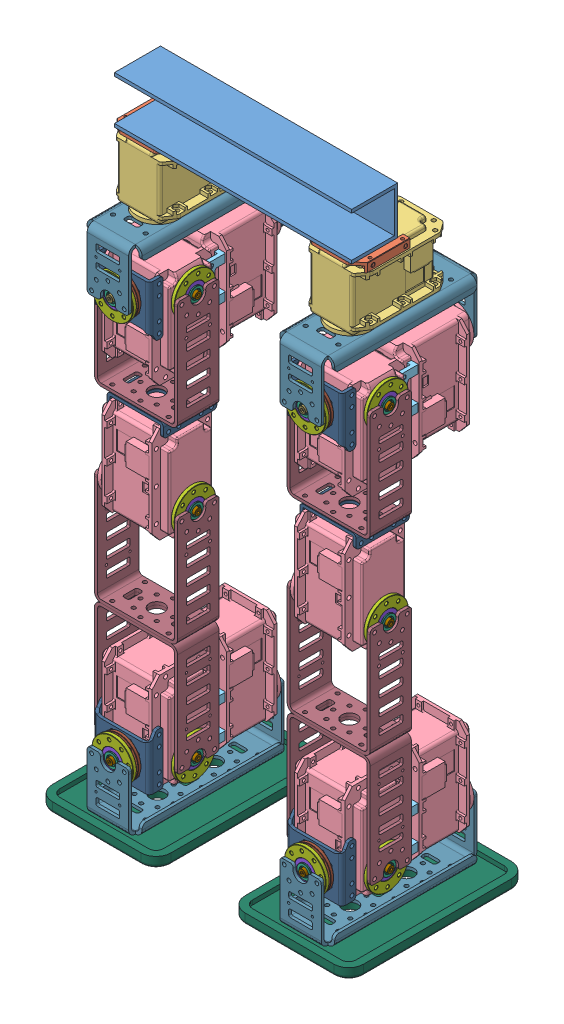
SolidWorks assembly leg, configuration Default. Lengths in mm.
Overall size (275.63 438.68 145.63).
96 component instances, 15 part files, 40 mates.
Components (placement in the parent):
- leg_l0-1: leg_l0 [Default] at origin size (170.2 83 62.1)
  - leg_body0-1: leg_body0 [Default] x (1 0 0) z (0 1 0) size (160 31 32)
  - FR05-B101_2017-1: FR05-B101_2017 [Default] at (-65 -39 -14) x (1 0 0) z (0 -1 0) size (39 35 6)
  - FR05-B101_2017-2: FR05-B101_2017 [Default] at (65 -39 -14) x (1 0 0) z (0 -1 0) size (39 35 6)
  - MX-64T_step-1: MX-64T_step [Default] at (-65 -39 -14) x (1 0 0) z (0 -1 0) size (40.2 62.1 50)
  - MX-64T_step-2: MX-64T_step [Default] at (65 -39 -14) x (1 0 0) z (0 -1 0) size (40.2 62.1 50)
- leg_l2-1: leg_l2 [Default] at (-65 -99.5 -13.5) x (0 0 1) z (-1 0 0) size (106.88 70.06 58.88)
  - MX-106T_step-1: MX-106T_step [Default] at origin size (40.2 65.92 55.3)
  - MX-106T_step-2: MX-106T_step [Default] at (-44 0 0) x (0 0 1) z (-1 0 0) size (40.2 65.92 55.3)
  - FR08-X101_2017-1: FR08-X101_2017 [Default] at (-27 -7 -17) x (0 -1 0) z (0 0 1) size (28 12.3 4.8)
  - FR08-X101_2017-2: FR08-X101_2017 [Default] at (-27 -7 17) x (0 1 0) z (0 0 -1) size (28 12.3 4.8)
  - RX64-CAP_2017-1: RX64-CAP_2017 [Default] at (0 0 -25.78) x (0.56381 0.825904 0) z (0 0 -1) size (9.5 9.5 2.2)
  - HN05-I101_2017-1: HN05-I101_2017 [Default] at (0 0 -26.02) x (0.824833 -0.565376 0) z (0.565376 0.824833 0) size (28 3.77 28)
  - MF128ZZ_2017-1: MF128ZZ_2017 [Default] at (0 0 -22.3) x (-0.923728 -0.383049 0) z (0.383049 -0.923728 0) size (14 3.48 14)
  - WB_M2.5X8_2017-1: WB_M2.5X8_2017 [Default] at (0 0 -28.08) x (0 0 1) z (0.825904 -0.56381 0) size (5.5 4.5 4.5)
  - FR05-S101_2017-1: FR05-S101_2017 [Default] at (24 0 0) x (0 1 0) z (0 0 1) size (36 9.31 38.02)
  - FR05-F101_2017-1: FR05-F101_2017 [Default] at (24 0 0) x (0 -0.707107 0.707107) z (1 0 0) size (27 27 5)
  - MF128ZZ_2017-2: MF128ZZ_2017 [Default] at (26.3 0 0) x (0 -1 0) z (0 0 1) size (14 3.48 14)
  - WB_M2.5X8_step-1: WB_M2.5X8_step [Default] at (32.08 0 0) x (-1 0 0) z (0 0.546944 0.837169) size (10.5 4.5 4.5)
  - HN05-I101_2017-2: HN05-I101_2017 [Default] at (30.02 0 0) x (0 -1 0) z (0 0 1) size (28 3.77 28)
  - RX64-CAP_2017-2: RX64-CAP_2017 [Default] at (29.78 0 0) x (0 0.837169 -0.546944) z (1 0 0) size (9.5 9.5 2.2)
- leg_l3-2: leg_l3 [Default] at (-87.8152 -185.4067 38.733) x (1 0 0) z (0 1 0) size (58.88 41.6 149.21)
  - HW-64106HXL_2017-1: HW-64106HXL_2017 [Default] at (-3.1848 38.233 13.9067) size (56 28 75)
  - FR05-S101_2017-1: FR05-S101_2017 [Default] at (22.8152 52.233 13.9067) x (0 -1 0) z (1 0 0) size (36 9.31 38.02)
  - MX-106T_step-1: MX-106T_step [Default] at (22.8152 52.233 -40.5933) x (0 1 0) z (-1 0 0) size (40.2 65.92 55.3)
  - HN05-I101_2017-1: HN05-I101_2017 [Default] at (48.8352 52.233 -40.5933) x (0 -0.637924 -0.7701) z (0 -0.7701 0.637924) size (28 3.77 28)
  - RX64-CAP_2017-1: RX64-CAP_2017 [Default] at (48.5952 52.233 -40.5933) x (0 0.837169 -0.546944) z (1 0 0) size (9.5 9.5 2.2)
  - MF128ZZ_2017-1: MF128ZZ_2017 [Default] at (45.1152 52.233 -40.5933) x (0 -0.162836 -0.986653) z (0 -0.986653 0.162836) size (14 3.48 14)
  - WB_M2.5X8_2017-1: WB_M2.5X8_2017 [Default] at (50.8952 52.233 -40.5933) x (-1 0 0) z (0 0.546944 0.837169) size (5.5 4.5 4.5)
- leg_l4-1: leg_l4 [Default] at (-107.1663 -366.6685 32.4894) x (1 0 0) z (0 1 0) size (56 28 150)
  - HW-64106HXL_2017-1: HW-64106HXL_2017 [Default] at (16.1663 31.9894 68.6685) size (56 28 75)
  - HW-64106HXL_2017-2: HW-64106HXL_2017 [Default] at (68.1663 31.9894 68.6685) x (-1 0 0) z (0 0 -1) size (56 28 75)
- leg_l5-1: leg_l5 [Default] at (-20.4188 -316.682 -47.3723) x (0.699193 -0.033567 0.714144) z (-0.673395 -0.366444 0.642073) size (104.02 99.97 119.36)
  - MX-106T_step-1: MX-106T_step [Default] at (-5.1915 -29.4269 71.3073) x (-0.714144 -0.278818 -0.642073) z (-0.699193 0.240141 0.673395) size (40.2 65.92 55.3)
  - MX-106T_step-2: MX-106T_step [Default] at (-36.6138 -41.6949 43.056) x (0.699193 -0.240141 -0.673395) z (-0.714144 -0.278818 -0.642073) size (40.2 65.92 55.3)
  - FR08-X101_2017-1: FR08-X101_2017 [Default] at (-36.5946 -26.3638 62.8539) x (-0.033567 0.929835 -0.366444) z (0.699193 -0.240141 -0.673395) size (28 12.3 4.8)
  - FR08-X101_2017-2: FR08-X101_2017 [Default] at (-12.8221 -34.5286 39.9585) x (0.033567 -0.929835 0.366444) z (-0.699193 0.240141 0.673395) size (28 12.3 4.8)
  - HN05-I101_2017-1: HN05-I101_2017 [Default] at (13.0015 -35.6754 53.7855) x (0.048348 -0.923861 0.379661) z (0.713296 0.298014 0.634347) size (28 3.77 28)
  - RX64-CAP_2017-1: RX64-CAP_2017 [Default] at (12.8337 -35.6178 53.9472) x (-0.430608 0.610431 -0.664793) z (0.699193 -0.240141 -0.673395) size (9.5 9.5 2.2)
  - HN05-I101_2017-2: HN05-I101_2017 [Default] at (16.2471 -21.0568 90.5823) x (0.601193 -0.714144 -0.35856) z (-0.35856 -0.642073 0.677626) size (28 3.77 28)
  - RX64-CAP_2017-2: RX64-CAP_2017 [Default] at (16.0757 -21.1237 90.4282) x (-0.307188 0.949038 -0.070448) z (0.714144 0.278818 0.642073) size (9.5 9.5 2.2)
  - MF128ZZ_2017-1: MF128ZZ_2017 [Default] at (10.4005 -34.7821 56.2906) x (0.048348 -0.923861 0.379661) z (0.713296 0.298014 0.634347) size (14 3.48 14)
  - WB_M2.5X8_2017-1: WB_M2.5X8_2017 [Default] at (14.4419 -36.1701 52.3983) x (-0.699193 0.240141 0.673395) z (0.570706 0.754788 0.323403) size (5.5 4.5 4.5)
  - MF128ZZ_2017-2: MF128ZZ_2017 [Default] at (13.5905 -22.094 88.1938) x (0.601193 -0.714144 -0.35856) z (-0.35856 -0.642073 0.677626) size (14 3.48 14)
  - WB_M2.5X8_2017-2: WB_M2.5X8_2017 [Default] at (17.7183 -20.4824 91.905) x (-0.714144 -0.278818 -0.642073) z (-0.628994 -0.146927 0.763399) size (5.5 4.5 4.5)
  - FR05-S101_2017-1: FR05-S101_2017 [Default] at (11.948 -22.7353 86.717) x (0.033567 -0.929835 0.366444) z (0.699193 -0.240141 -0.673395) size (36 9.31 38.02)
  - FR05-F101_2017-1: FR05-F101_2017 [Default] at (11.948 -22.7353 86.717) x (0.699193 -0.240141 -0.673395) z (0.714144 0.278818 0.642073) size (27 27 5)
- leg_l6-1: leg_l6 [Default] at (-15.5913 -468.4394 11.5308) x (0 0 -1) z (0 1 0) size (120 80 44)
  - HW-64106HXW_2017-1: HW-64106HXW_2017 [Default] at (-3.9692 33.4087 61.4394) size (105 37.08 40)
  - foot_2017-1: foot_2017 [Default] at (44.5308 49.4087 57.4394) x (-1 0 0) z (0 1 0) size (120 7 80)
- HW-64106HXW_2017-3: HW-64106HXW_2017 [Default] at (81 -62.5 -81.5) x (0 0 1) z (0 -1 0) size (105 37.08 40)
- leg_l2-2: leg_l2 [Default] at (65 -99.5 -13.5) x (0 0 1) z (-1 0 0) size (106.88 70.06 58.88)
  - MX-106T_step-1: MX-106T_step [Default] at origin size (40.2 65.92 55.3)
  - MX-106T_step-2: MX-106T_step [Default] at (-44 0 0) x (0 0 1) z (-1 0 0) size (40.2 65.92 55.3)
  - FR08-X101_2017-1: FR08-X101_2017 [Default] at (-27 -7 -17) x (0 -1 0) z (0 0 1) size (28 12.3 4.8)
  - FR08-X101_2017-2: FR08-X101_2017 [Default] at (-27 -7 17) x (0 1 0) z (0 0 -1) size (28 12.3 4.8)
  - RX64-CAP_2017-1: RX64-CAP_2017 [Default] at (0 0 -25.78) x (0.56381 0.825904 0) z (0 0 -1) size (9.5 9.5 2.2)
  - HN05-I101_2017-1: HN05-I101_2017 [Default] at (0 0 -26.02) x (0.824833 -0.565376 0) z (0.565376 0.824833 0) size (28 3.77 28)
  - MF128ZZ_2017-1: MF128ZZ_2017 [Default] at (0 0 -22.3) x (-0.923728 -0.383049 0) z (0.383049 -0.923728 0) size (14 3.48 14)
  - WB_M2.5X8_2017-1: WB_M2.5X8_2017 [Default] at (0 0 -28.08) x (0 0 1) z (0.825904 -0.56381 0) size (5.5 4.5 4.5)
  - FR05-S101_2017-1: FR05-S101_2017 [Default] at (24 0 0) x (0 1 0) z (0 0 1) size (36 9.31 38.02)
  - FR05-F101_2017-1: FR05-F101_2017 [Default] at (24 0 0) x (0 -0.707107 0.707107) z (1 0 0) size (27 27 5)
  - MF128ZZ_2017-2: MF128ZZ_2017 [Default] at (26.3 0 0) x (0 -1 0) z (0 0 1) size (14 3.48 14)
  - WB_M2.5X8_step-1: WB_M2.5X8_step [Default] at (32.08 0 0) x (-1 0 0) z (0 0.546944 0.837169) size (10.5 4.5 4.5)
  - HN05-I101_2017-2: HN05-I101_2017 [Default] at (30.02 0 0) x (0 -1 0) z (0 0 1) size (28 3.77 28)
  - RX64-CAP_2017-2: RX64-CAP_2017 [Default] at (29.78 0 0) x (0 0.837169 -0.546944) z (1 0 0) size (9.5 9.5 2.2)
- leg_l3-3: leg_l3 [Default] at (42.1848 -185.4067 38.733) x (1 0 0) z (0 1 0) size (58.88 41.6 149.21)
  - HW-64106HXL_2017-1: HW-64106HXL_2017 [Default] at (-3.1848 38.233 13.9067) size (56 28 75)
  - FR05-S101_2017-1: FR05-S101_2017 [Default] at (22.8152 52.233 13.9067) x (0 -1 0) z (1 0 0) size (36 9.31 38.02)
  - MX-106T_step-1: MX-106T_step [Default] at (22.8152 52.233 -40.5933) x (0 1 0) z (-1 0 0) size (40.2 65.92 55.3)
  - HN05-I101_2017-1: HN05-I101_2017 [Default] at (48.8352 52.233 -40.5933) x (0 -0.637924 -0.7701) z (0 -0.7701 0.637924) size (28 3.77 28)
  - RX64-CAP_2017-1: RX64-CAP_2017 [Default] at (48.5952 52.233 -40.5933) x (0 0.837169 -0.546944) z (1 0 0) size (9.5 9.5 2.2)
  - MF128ZZ_2017-1: MF128ZZ_2017 [Default] at (45.1152 52.233 -40.5933) x (0 -0.162836 -0.986653) z (0 -0.986653 0.162836) size (14 3.48 14)
  - WB_M2.5X8_2017-1: WB_M2.5X8_2017 [Default] at (50.8952 52.233 -40.5933) x (-1 0 0) z (0 0.546944 0.837169) size (5.5 4.5 4.5)
- leg_l4-2: leg_l4 [Default] at (22.8337 -366.6685 32.4894) x (1 0 0) z (0 1 0) size (56 28 150)
  - HW-64106HXL_2017-1: HW-64106HXL_2017 [Default] at (16.1663 31.9894 68.6685) size (56 28 75)
  - HW-64106HXL_2017-2: HW-64106HXL_2017 [Default] at (68.1663 31.9894 68.6685) x (-1 0 0) z (0 0 -1) size (56 28 75)
- leg_l5-2: leg_l5 [Default] at (109.5812 -316.682 -47.3723) x (0.699193 -0.033567 0.714144) z (-0.673395 -0.366444 0.642073) size (104.02 99.97 119.36)
  - MX-106T_step-1: MX-106T_step [Default] at (-5.1915 -29.4269 71.3073) x (-0.714144 -0.278818 -0.642073) z (-0.699193 0.240141 0.673395) size (40.2 65.92 55.3)
  - MX-106T_step-2: MX-106T_step [Default] at (-36.6138 -41.6949 43.056) x (0.699193 -0.240141 -0.673395) z (-0.714144 -0.278818 -0.642073) size (40.2 65.92 55.3)
  - FR08-X101_2017-1: FR08-X101_2017 [Default] at (-36.5946 -26.3638 62.8539) x (-0.033567 0.929835 -0.366444) z (0.699193 -0.240141 -0.673395) size (28 12.3 4.8)
  - FR08-X101_2017-2: FR08-X101_2017 [Default] at (-12.8221 -34.5286 39.9585) x (0.033567 -0.929835 0.366444) z (-0.699193 0.240141 0.673395) size (28 12.3 4.8)
  - HN05-I101_2017-1: HN05-I101_2017 [Default] at (13.0015 -35.6754 53.7855) x (0.048348 -0.923861 0.379661) z (0.713296 0.298014 0.634347) size (28 3.77 28)
  - RX64-CAP_2017-1: RX64-CAP_2017 [Default] at (12.8337 -35.6178 53.9472) x (-0.430608 0.610431 -0.664793) z (0.699193 -0.240141 -0.673395) size (9.5 9.5 2.2)
  - HN05-I101_2017-2: HN05-I101_2017 [Default] at (16.2471 -21.0568 90.5823) x (0.601193 -0.714144 -0.35856) z (-0.35856 -0.642073 0.677626) size (28 3.77 28)
  - RX64-CAP_2017-2: RX64-CAP_2017 [Default] at (16.0757 -21.1237 90.4282) x (-0.307188 0.949038 -0.070448) z (0.714144 0.278818 0.642073) size (9.5 9.5 2.2)
  - MF128ZZ_2017-1: MF128ZZ_2017 [Default] at (10.4005 -34.7821 56.2906) x (0.048348 -0.923861 0.379661) z (0.713296 0.298014 0.634347) size (14 3.48 14)
  - WB_M2.5X8_2017-1: WB_M2.5X8_2017 [Default] at (14.4419 -36.1701 52.3983) x (-0.699193 0.240141 0.673395) z (0.570706 0.754788 0.323403) size (5.5 4.5 4.5)
  - MF128ZZ_2017-2: MF128ZZ_2017 [Default] at (13.5905 -22.094 88.1938) x (0.601193 -0.714144 -0.35856) z (-0.35856 -0.642073 0.677626) size (14 3.48 14)
  - WB_M2.5X8_2017-2: WB_M2.5X8_2017 [Default] at (17.7183 -20.4824 91.905) x (-0.714144 -0.278818 -0.642073) z (-0.628994 -0.146927 0.763399) size (5.5 4.5 4.5)
  - FR05-S101_2017-1: FR05-S101_2017 [Default] at (11.948 -22.7353 86.717) x (0.033567 -0.929835 0.366444) z (0.699193 -0.240141 -0.673395) size (36 9.31 38.02)
  - FR05-F101_2017-1: FR05-F101_2017 [Default] at (11.948 -22.7353 86.717) x (0.699193 -0.240141 -0.673395) z (0.714144 0.278818 0.642073) size (27 27 5)
- leg_l6-2: leg_l6 [Default] at (114.4087 -468.4394 11.5308) x (0 0 -1) z (0 1 0) size (120 80 44)
  - HW-64106HXW_2017-1: HW-64106HXW_2017 [Default] at (-3.9692 33.4087 61.4394) size (105 37.08 40)
  - foot_2017-1: foot_2017 [Default] at (44.5308 49.4087 57.4394) x (-1 0 0) z (0 1 0) size (120 7 80)
- HW-64106HXW_2017-5: HW-64106HXW_2017 [Default] at (-49 -62.5 -81.5) x (0 0 1) z (0 -1 0) size (105 37.08 40)
Mates (geometry in assembly coordinates):
- Concentric3: concentric anti-aligned: cylinder of leg_l2-1/HN05-I101_2017-1 through (-38.98 -99.5 -13.5) axis (-1 0 0) radius 14; cylinder of leg_l3-2/HW-64106HXL_2017-1 through (-37 -99.5 -13.5) axis (1 0 0) radius 5.1
- Concentric4: concentric anti-aligned: cylinder of leg_l3-2/HN05-I101_2017-1 through (-38.98 -226 -13.5) axis (-1 0 0) radius 14; cylinder of leg_l4-1/HW-64106HXL_2017-1 through (-37 -226 -13.5) axis (1 0 0) radius 5.1
- Concentric5: concentric anti-aligned: cylinder of leg_l4-1/HW-64106HXL_2017-2 through (-93 -370 -13.5) axis (-1 0 0) radius 5.1; cylinder of leg_l5-1/MX-106T_step-1 through (-96.19 -370 -13.5) axis (1 0 0) radius 5
- Coincident5: coincident anti-aligned: plane of leg_l4-1/HW-64106HXL_2017-2 through (-91 -370 -13.5) normal (1 0 0); plane of leg_l5-1/MX-106T_step-1 through (-91 -370 -13.5) normal (-1 0 0)
- Coincident6: coincident anti-aligned: plane of leg_l2-1/MX-106T_step-1 through (-91 -99.5 -13.5) normal (-1 0 0); plane of leg_l3-2/HW-64106HXL_2017-1 through (-91 -99.5 -13.5) normal (1 0 0)
- Coincident7: coincident anti-aligned: plane of leg_l2-1/MX-106T_step-1 through (-91 -99.5 -13.5) normal (-1 0 0); plane of leg_l3-2/HW-64106HXL_2017-1 through (-91 -99.5 -13.5) normal (1 0 0)
- Coincident8: coincident anti-aligned: plane of leg_l3-2/MX-106T_step-1 through (-91 -226 -13.5) normal (-1 0 0); plane of leg_l4-1/HW-64106HXL_2017-1 through (-91 -226 -13.5) normal (1 0 0)
- Concentric6: concentric anti-aligned: cylinder of leg_l5-1/MX-106T_step-2 through (-65 -370 -88.69) axis (0 0 1) radius 14; cylinder of leg_l6-1/HW-64106HXW_2017-1 through (-65 -370 -85.5) axis (0 0 -1) radius 5.1
- Coincident9: coincident anti-aligned: plane of leg_l5-1/MX-106T_step-2 through (-65 -370 -83.5) normal (0 0 -1); plane of leg_l6-1/HW-64106HXW_2017-1 through (-65 -384.9161 -83.5) normal (0 0 1)
- Concentric7: concentric anti-aligned: cylinder of leg_l0-1/MX-64T_step-2 through (65 -67.375 -14) axis (0 1 0) radius 5; cylinder of HW-64106HXW_2017-3 through (65 -180.8213 -14) axis (0 -1 0) radius 5.1
- Coincident10: coincident anti-aligned: plane of leg_l0-1/MX-64T_step-2 through (65 -62.5 -14) normal (0 -1 0); plane of HW-64106HXW_2017-3 through (65 -62.5 -7.75) normal (0 1 0)
- Concentric8: concentric aligned: cylinder of HW-64106HXW_2017-3 through (65 -99.5 19.5) axis (0 0 1) radius 5.1; cylinder of leg_l2-2/MX-106T_step-2 through (65 -99.5 -88.69) axis (0 0 1) radius 5
- Coincident11: coincident anti-aligned: plane of HW-64106HXW_2017-3 through (65 -84.5839 -83.5) normal (0 0 1); plane of leg_l2-2/MX-106T_step-2 through (65 -99.5 -83.5) normal (0 0 -1)
- Concentric9: concentric aligned: cylinder of leg_l2-2/MX-106T_step-1 through (33.81 -99.5 -13.5) axis (1 0 0) radius 5; cylinder of leg_l3-3/HW-64106HXL_2017-1 through (39 -99.5 -13.5) axis (1 0 0) radius 5.1
- Coincident12: coincident anti-aligned: plane of leg_l2-2/MX-106T_step-1 through (39 -99.5 -13.5) normal (-1 0 0); plane of leg_l3-3/HW-64106HXL_2017-1 through (39 -99.5 -13.5) normal (1 0 0)
- Concentric10: concentric aligned: cylinder of leg_l3-3/MX-106T_step-1 through (33.81 -226 -13.5) axis (1 0 0) radius 5; cylinder of leg_l4-2/HW-64106HXL_2017-1 through (39 -226 -13.5) axis (1 0 0) radius 5.1
- Coincident13: coincident anti-aligned: plane of leg_l3-3/MX-106T_step-1 through (39 -226 -13.5) normal (-1 0 0); plane of leg_l4-2/HW-64106HXL_2017-1 through (39 -226 -13.5) normal (1 0 0)
- Concentric13: concentric anti-aligned: cylinder of leg_l4-2/HW-64106HXL_2017-2 through (37 -370 -13.5) axis (-1 0 0) radius 5.1; cylinder of leg_l5-2/MX-106T_step-1 through (33.81 -370 -13.5) axis (1 0 0) radius 5
- Coincident16: coincident anti-aligned: plane of leg_l4-2/HW-64106HXL_2017-2 through (39 -370 -13.5) normal (1 0 0); plane of leg_l5-2/MX-106T_step-1 through (39 -370 -13.5) normal (-1 0 0)
- Parallel3: parallel anti-aligned: plane of leg_l2-1/MX-106T_step-1 through (-65 -99.5 -13.5) normal (0 0 1); plane of leg_l3-2/HW-64106HXL_2017-1 through (-91 -171.5 0.5) normal (0 0 -1)
- Parallel4: parallel aligned: plane of leg_l3-2/MX-106T_step-1 through (-65 -226 -13.5) normal (0 0 -1); plane of leg_l4-1/HW-64106HXL_2017-1 through (-91 -298 0.5) normal (0 0 -1)
- Parallel5: parallel aligned: plane of leg_l4-1/HW-64106HXL_2017-2 through (-39 -298 0.5) normal (0 0 -1); plane of leg_l5-1/MX-106T_step-1 through (-65 -370 -13.5) normal (0 0 -1)
- Parallel6: parallel aligned: plane of leg_l5-1/MX-106T_step-1 through (-65 -370 -13.5) normal (-1 0 0); plane of leg_l6-1/HW-64106HXW_2017-1 through (-49 -407 15.5) normal (-1 0 0)
- Parallel7: parallel anti-aligned: plane of leg_l0-1 through (0 0 0) normal (1 0 0); plane of HW-64106HXW_2017-3 through (81 -62.5 -81.5) normal (-1 0 0)
- Parallel8: parallel aligned: plane of HW-64106HXW_2017-3 through (81 -62.5 -81.5) normal (-1 0 0); plane of leg_l2-2/MX-106T_step-1 through (65 -99.5 -13.5) normal (-1 0 0)
- Parallel9: parallel anti-aligned: plane of leg_l2-2/MX-106T_step-1 through (65 -99.5 -13.5) normal (0 0 1); plane of leg_l3-3/HW-64106HXL_2017-1 through (39 -171.5 0.5) normal (0 0 -1)
- Parallel10: parallel aligned: plane of leg_l3-3/MX-106T_step-1 through (65 -226 -13.5) normal (0 0 -1); plane of leg_l4-2/HW-64106HXL_2017-1 through (39 -298 0.5) normal (0 0 -1)
- Parallel11: parallel aligned: plane of leg_l4-2/HW-64106HXL_2017-2 through (91 -298 0.5) normal (0 0 -1); plane of leg_l5-2/MX-106T_step-1 through (65 -370 -13.5) normal (0 0 -1)
- Coincident29: coincident aligned: plane of leg_l0-1 through (0 0 0) normal (1 0 0); plane of assembly through (0 0 0) normal (1 0 0)
- Coincident30: coincident aligned: plane of leg_l0-1 through (0 0 0) normal (0 0 1); plane of assembly through (0 0 0) normal (0 0 1)
- Coincident31: coincident aligned: plane of leg_l0-1 through (0 0 0) normal (0 1 0); plane of assembly through (0 0 0) normal (0 1 0)
- Concentric18: concentric anti-aligned: cylinder of leg_l0-1/MX-64T_step-1 through (-65 -67.375 -14) axis (0 1 0) radius 5; cylinder of HW-64106HXW_2017-5 through (-65 -180.8213 -14) axis (0 -1 0) radius 5.1
- Coincident38: coincident anti-aligned: plane of leg_l0-1/MX-64T_step-1 through (-65 -62.5 -14) normal (0 -1 0); plane of HW-64106HXW_2017-5 through (-65 -62.5 -7.75) normal (0 1 0)
- Concentric19: concentric aligned: cylinder of leg_l2-1/MX-106T_step-2 through (-65 -99.5 -88.69) axis (0 0 1) radius 5; cylinder of HW-64106HXW_2017-5 through (-65 -99.5 19.5) axis (0 0 1) radius 5.1
- Coincident39: coincident anti-aligned: plane of leg_l2-1/MX-106T_step-2 through (-65 -99.5 -83.5) normal (0 0 -1); plane of HW-64106HXW_2017-5 through (-65 -84.5839 -83.5) normal (0 0 1)
- Parallel17: parallel anti-aligned: plane of leg_l0-1/MX-64T_step-1 through (-65 -39 -14) normal (1 0 0); plane of HW-64106HXW_2017-5 through (-49 -62.5 -81.5) normal (-1 0 0)
- Parallel18: parallel aligned: plane of leg_l2-1/MX-106T_step-1 through (-65 -99.5 -13.5) normal (-1 0 0); plane of HW-64106HXW_2017-5 through (-49 -62.5 -81.5) normal (-1 0 0)
- Concentric20: concentric anti-aligned: cylinder of leg_l5-2/MX-106T_step-2 through (65 -370 -88.69) axis (0 0 1) radius 5; cylinder of leg_l6-2/HW-64106HXW_2017-1 through (65 -370 -85.5) axis (0 0 -1) radius 5.1
- Coincident42: coincident anti-aligned: plane of leg_l5-2/MX-106T_step-2 through (65 -370 -83.5) normal (0 0 -1); plane of leg_l6-2/HW-64106HXW_2017-1 through (65 -384.9161 -83.5) normal (0 0 1)
- Parallel19: parallel aligned: plane of leg_l5-2/MX-106T_step-1 through (65 -370 -13.5) normal (-1 0 0); plane of leg_l6-2/HW-64106HXW_2017-1 through (81 -407 15.5) normal (-1 0 0)
